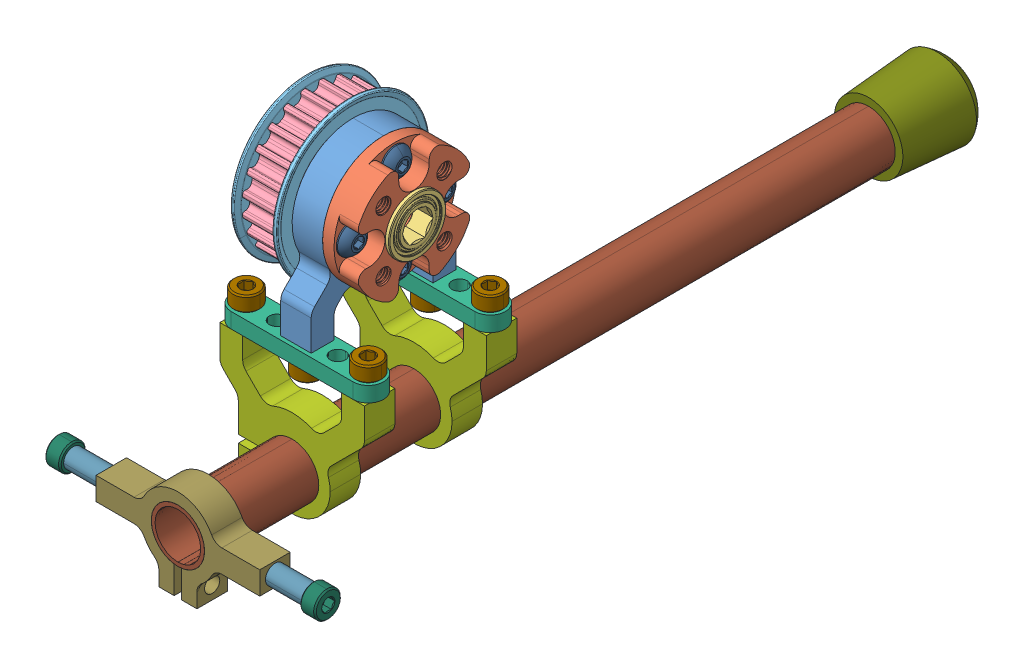
SolidWorks assembly Link4_Assembly, configuration Default. Lengths in mm.
Overall size (71.02 98.08 204.48).
44 component instances, 17 part files, 56 mates.
Components (placement in the parent):
- 1200-0032-0001-1: 1200-0032-0001 [Default] at (-4 0 0) x (0 0 -1) z (0 -1 0) size (38 8.01 40)
- 1505-0032-0080-1: 1505-0032-0080 [Default] at (4 0 0) x (0 -0.707107 -0.707107) z (0 -0.707107 0.707107) size (31.97 8.01 31.97)
- 1611-0514-4008-1: 1611-0514-4008 [Default] at (8 0 0) x (0 -0.88626 -0.463188) z (0 -0.463188 0.88626) size (15 5 15)
- 3411-0014-0024 Assembly-1: 3411-0014-0024 Assembly [Default] at (-5.9537 9.4234 37.3045) x (-1 0 0) z (0 -0.707107 -0.707107) size (12.11 52.82 52.82)
  - 3411-0014-0024 Assembly.STEP-1: 3411-0014-0024 Assembly.STEP [Default] at origin size (12.11 52.82 52.82)
    - 3411-0014-0024 Body.STEP-1: 3411-0014-0024 Body.STEP [Default] at (-9.2805 19.7149 33.0416) size (12.02 36.82 36.82)
    - 3411-0014-0024 Ring.STEP-1: 3411-0014-0024 Ring.STEP [Default] at (-0.5737 19.7149 33.0416) x (0 1 0) z (0 0 1) size (40.44 1.43 40.44)
    - 3411-0014-0024 Ring.STEP-2: 3411-0014-0024 Ring.STEP [Default] at (8.6763 19.7149 33.0416) x (0 0.381849 -0.924225) z (0 -0.924225 -0.381849) size (40.44 1.43 40.44)
- 1611-0514-4008-2: 1611-0514-4008 [Default] at (-12.01 0 0) x (0 -0.997513 -0.070476) z (0 0.070476 -0.997513) size (15 5 15)
- 1102-0005-0040-2: 1102-0005-0040 [Default] at (0 -28 -16) size (40 4 8)
- 1400-0032-0014 assembly-1: 1400-0032-0014 assembly [Default] at (-6.7355 -44.9859 -19.629) x (-1 0 0) z (0 0 1) size (38 34 8)
  - 1400-0032-0014 assembly.STEP-1: 1400-0032-0014 assembly.STEP [Default] at origin size (38 34 8)
    - 1400-0032-0014.STEP-1: 1400-0032-0014.STEP [Default] at (-6.7355 7.0141 -0.371) size (38 34 8)
    - 2800-0004-0012_90128A207.STEP-1: 2800-0004-0012_90128A207.STEP [Default] at (3.8927 0.0141 3.629) x (1 0 0) z (0 -1 0) size (7 7 16.01)
- 2800-0004-0010-1: 2800-0004-0010 [Default] at (16 -34 -16) x (1 0 0) z (0 -1 0) size (7 7 14.01)
- 2800-0004-0010-3: 2800-0004-0010 [Default] at (-16 -34 -16) x (0.99955 0 0.030006) z (0 -1 0) size (7 7 14.01)
- 2800-0004-0010-4: 2800-0004-0010 [Default] at (0 -18 -16) x (-0.87492 0 -0.484268) z (0 1 0) size (7 7 14.01)
- 2800-0004-0010-5: 2800-0004-0010 [Default] at (-16 -34 16) x (0.99955 0 -0.030006) z (0 -1 0) size (7 7 14.01)
- 1102-0005-0040-3: 1102-0005-0040 [Default] at (0 -28 16) size (40 4 8)
- 2800-0004-0010-6: 2800-0004-0010 [Default] at (0 -18 16) x (-0.87492 0 0.484268) z (0 1 0) size (7 7 14.01)
- 2800-0004-0010-7: 2800-0004-0010 [Default] at (16 -34 16) x (1 0 0) z (0 -1 0) size (7 7 14.01)
- 1400-0032-0014 assembly-4: 1400-0032-0014 assembly [Default] at (-6.7355 -44.9859 12.371) x (-1 0 0) z (0 0 1) size (38 34 8)
  - 1400-0032-0014 assembly.STEP-1: 1400-0032-0014 assembly.STEP [Default] at origin size (38 34 8)
    - 1400-0032-0014.STEP-1: 1400-0032-0014.STEP [Default] at (-6.7355 7.0141 -0.371) size (38 34 8)
    - 2800-0004-0012_90128A207.STEP-1: 2800-0004-0012_90128A207.STEP [Default] at (3.8927 0.0141 3.629) x (1 0 0) z (0 -1 0) size (7 7 16.01)
- 2800-0004-0010-16: 2800-0004-0010 [Default] at (-1.91 11.3137 0) x (0 -0.40941 0.912351) z (1 0 0) size (7 7 14.01)
- 2800-0004-0010-17: 2800-0004-0010 [Default] at (-1.91 0 -11.3137) x (0 -0.40941 0.912351) z (1 0 0) size (7 7 14.01)
- 2800-0004-0010-18: 2800-0004-0010 [Default] at (-1.91 -11.3137 0) x (0 -0.40941 0.912351) z (1 0 0) size (7 7 14.01)
- 2800-0004-0010-19: 2800-0004-0010 [Default] at (-1.91 0 11.3137) x (0 -0.40941 0.912351) z (1 0 0) size (7 7 14.01)
- 2802-0004-0008-1: 2802-0004-0008 [Default] at (9.2 -11.6137 0) x (0 0 -1) z (1 0 0) size (7.6 7.6 10.21)
- 2802-0004-0008-2: 2802-0004-0008 [Default] at (9.2 11.6137 0) x (0 0 -1) z (1 0 0) size (7.6 7.6 10.21)
- 2802-0004-0008-3: 2802-0004-0008 [Default] at (9.2 0 -11.6137) x (0 0 -1) z (1 0 0) size (7.6 7.6 10.21)
- 2802-0004-0008-4: 2802-0004-0008 [Default] at (9.2 0 11.6137) x (0 0 -1) z (1 0 0) size (7.6 7.6 10.21)
- 4100-1214-0200-1: 4100-1214-0200 [Default] at (0 -52 50) x (1 0 0) z (0 1 0) size (14 200 14)
- 1402-0043-0014-1: 1402-0043-0014 [Default] at (-3.9775 -62.2331 37.3554) x (0 -1 0) z (0 0 1) size (24.13 43.01 18.01)
  - 1402-0043-0014.step-1: 1402-0043-0014.step [Default] at origin size (24.13 43.01 18.01)
    - 1402-0043-0014 without hardware.step-1: 1402-0043-0014 without hardware.step [Default] at (-10.2331 3.9775 4.6446) x (0 -1 0) z (1 0 0) size (43.01 8 24.13)
    - 2800-0004-0010.step-1: 2800-0004-0010.step [Default] at (0.3951 -1.0225 8.6446) size (7 7 14.01)
- 1502-0005-0100-1: 1502-0005-0100 [Default] at (-21.5 -52 46) x (0 1 0) z (0 0 1) size (5 10 5)
- 2800-0004-0018-1: 2800-0004-0018 [Default] at (-13.5 -52 46) x (0 -0.999802 -0.019876) z (1 0 0) size (7 7 22.01)
- 2800-0004-0018-2: 2800-0004-0018 [Default] at (13.5 -52 46) x (0 -0.999802 -0.019876) z (-1 0 0) size (7 7 22.01)
- 14mm Chair leg tip cap-1: 14mm Chair leg tip cap [Default] at (0 -52 -150) x (-0.792237 0.610214 0) z (0.610214 0.792237 0) size (20.65 23.07 20.65)
- Linear_Disp_Sensor_404R1KL1.0-1: Linear_Disp_Sensor_404R1KL1.0 [Default] at (-11.95 -52 -127.2937) x (0 0 -1) z (1 0 0) size (47.49 12.7 8.51) (hidden)
- 1502-0005-0100-3: 1502-0005-0100 [Default] at (21.5 -52 46) x (0 1 0) z (0 0 -1) size (5 10 5)
Mates (geometry in assembly coordinates):
- Coincident1: coincident anti-aligned: plane of 1200-0032-0001-1 through (-4 0 0) normal (0 -1 0)
- Symmetric1: symmetric aligned: plane of 1200-0032-0001-1 through (4 0 0) normal (1 0 0); plane of 1200-0032-0001-1 through (-4 0 0) normal (-1 0 0)
- Symmetric2: symmetric aligned: plane of 1200-0032-0001-1 through (-22.0392 0 -19) normal (0 0 -1); plane of 1200-0032-0001-1 through (-22.0392 0 19) normal (0 0 1)
- Concentric2: concentric anti-aligned: cylinder of 1200-0032-0001-1 through (4 0 0) axis (-1 0 0) radius 7; cylinder of 1505-0032-0080-1 through (4 0 0) axis (1 0 0) radius 7
- Coincident2: coincident anti-aligned: circle of 1200-0032-0001-1; cylinder of 1505-0032-0080-1 through (4 0 11.3137) axis (1 0 0) radius 2
- Coincident3: coincident anti-aligned: plane of 1200-0032-0001-1 through (4 0 0) normal (1 0 0); plane of 1505-0032-0080-1 through (4 0 0) normal (-1 0 0)
- Concentric3: concentric aligned: cylinder of 1200-0032-0001-1 through (4 0 0) axis (-1 0 0) radius 7; cylinder of 3411-0014-0024 Assembly-1/3411-0014-0024 Assembly.STEP-1/3411-0014-0024 Body.STEP-1 through (-11.91 0 0) axis (-1 0 0) radius 7
- Concentric4: concentric anti-aligned: circle of 1200-0032-0001-1; cylinder of 3411-0014-0024 Assembly-1/3411-0014-0024 Assembly.STEP-1/3411-0014-0024 Body.STEP-1 through (-4 11.3137 0) axis (-1 0 0) radius 2
- Coincident5: coincident anti-aligned: plane of 1200-0032-0001-1 through (-4 0 0) normal (-1 0 0); plane of 3411-0014-0024 Assembly-1/3411-0014-0024 Assembly.STEP-1/3411-0014-0024 Body.STEP-1 through (-4 0 0) normal (1 0 0)
- Concentric5: concentric anti-aligned: cylinder of 1505-0032-0080-1 through (4 0 0) axis (1 0 0) radius 7; cylinder of 1611-0514-4008-1 through (12 0 0) axis (-1 0 0) radius 7
- Coincident6: coincident anti-aligned: plane of 1505-0032-0080-1 through (12 0 0) normal (1 0 0); plane of 1611-0514-4008-1 through (12 0 0) normal (-1 0 0)
- Concentric6: concentric anti-aligned: cylinder of 3411-0014-0024 Assembly-1/3411-0014-0024 Assembly.STEP-1/3411-0014-0024 Body.STEP-1 through (-11.91 0 0) axis (-1 0 0) radius 7; cylinder of 1611-0514-4008-2 through (-16.01 0 0) axis (1 0 0) radius 7
- Coincident8: coincident anti-aligned: plane of 3411-0014-0024 Assembly-1/3411-0014-0024 Assembly.STEP-1/3411-0014-0024 Body.STEP-1 through (-16.01 0 0) normal (-1 0 0); plane of 1611-0514-4008-2 through (-16.01 0 0) normal (1 0 0)
- Coincident12: coincident anti-aligned: plane of 1200-0032-0001-1 through (-22.0392 -24 0) normal (0 -1 0); plane of 1102-0005-0040-2 through (-16 -24 -16) normal (0 1 0)
- Coincident13: coincident aligned: circle of 1200-0032-0001-1; cylinder of 1102-0005-0040-2 through (0 -24 -16) axis (0 1 0) radius 2
- Parallel2: parallel aligned: plane of 1200-0032-0001-1 through (-22.0392 0 -19) normal (0 0 -1); plane of 1102-0005-0040-2 through (-16 -24 -20) normal (0 0 -1)
- Coincident14: coincident anti-aligned: plane of 1102-0005-0040-2 through (-16 -28 -16) normal (0 -1 0); plane of 1400-0032-0014 assembly-1/1400-0032-0014 assembly.STEP-1/1400-0032-0014.STEP-1 through (13 -28 -12) normal (0 1 0)
- Coincident15: coincident anti-aligned: cylinder of 1102-0005-0040-2 through (16 -24 -16) axis (0 1 0) radius 2; circle of 1400-0032-0014 assembly-1/1400-0032-0014 assembly.STEP-1/1400-0032-0014.STEP-1
- Coincident16: coincident aligned: plane of 1102-0005-0040-2 through (-16 -24 -20) normal (0 0 -1); plane of 1400-0032-0014 assembly-1/1400-0032-0014 assembly.STEP-1/1400-0032-0014.STEP-1 through (0 -52 -20) normal (0 0 -1)
- Coincident22: coincident anti-aligned: plane of 1102-0005-0040-2 through (-16 -24 -16) normal (0 1 0); plane of 2800-0004-0010-1 through (16 -24 -16) normal (0 -1 0)
- Concentric10: concentric anti-aligned: cylinder of 1102-0005-0040-2 through (16 -24 -16) axis (0 1 0) radius 2; cylinder of 2800-0004-0010-1 through (16 -20 -16) axis (0 -1 0) radius 3.5
- Concentric11: concentric anti-aligned: cylinder of 1102-0005-0040-2 through (-16 -24 -16) axis (0 1 0) radius 2; cylinder of 2800-0004-0010-3 through (-16 -20 -16) axis (0 -1 0) radius 3.5
- Coincident23: coincident anti-aligned: plane of 1102-0005-0040-2 through (-16 -24 -16) normal (0 1 0); plane of 2800-0004-0010-3 through (-16 -24 -16) normal (0 -1 0)
- Concentric12: concentric aligned: cylinder of 1102-0005-0040-2 through (0 -24 -16) axis (0 1 0) radius 2; cylinder of 2800-0004-0010-4 through (0 -32 -16) axis (0 1 0) radius 3.5
- Coincident24: coincident anti-aligned: plane of 1102-0005-0040-2 through (-16 -28 -16) normal (0 -1 0); plane of 2800-0004-0010-4 through (0 -28 -16) normal (0 1 0)
- Coincident29: coincident aligned: plane of 2800-0004-0010-16 through (-11.91 11.3137 0) normal (1 0 0); plane of 2800-0004-0010-17 through (-11.91 0 -11.3137) normal (1 0 0)
- Coincident30: coincident aligned: plane of 2800-0004-0010-17 through (-11.91 0 -11.3137) normal (1 0 0); plane of 2800-0004-0010-18 through (-11.91 -11.3137 0) normal (1 0 0)
- Coincident31: coincident aligned: plane of 2800-0004-0010-17 through (-11.91 0 -11.3137) normal (1 0 0); plane of 2800-0004-0010-19 through (-11.91 0 11.3137) normal (1 0 0)
- Coincident32: coincident anti-aligned: plane of 3411-0014-0024 Assembly-1/3411-0014-0024 Assembly.STEP-1/3411-0014-0024 Body.STEP-1 through (-11.91 0 0) normal (-1 0 0); plane of 2800-0004-0010-17 through (-11.91 0 -11.3137) normal (1 0 0)
- Concentric17: concentric anti-aligned: cylinder of 3411-0014-0024 Assembly-1/3411-0014-0024 Assembly.STEP-1/3411-0014-0024 Body.STEP-1 through (-11.91 0 -11.3137) axis (-1 0 0) radius 3.6; cylinder of 2800-0004-0010-17 through (-15.91 0 -11.3137) axis (1 0 0) radius 3.5
- Concentric18: concentric anti-aligned: cylinder of 3411-0014-0024 Assembly-1/3411-0014-0024 Assembly.STEP-1/3411-0014-0024 Body.STEP-1 through (-11.91 11.3137 0) axis (-1 0 0) radius 3.6; cylinder of 2800-0004-0010-16 through (-15.91 11.3137 0) axis (1 0 0) radius 3.5
- Concentric19: concentric anti-aligned: cylinder of 3411-0014-0024 Assembly-1/3411-0014-0024 Assembly.STEP-1/3411-0014-0024 Body.STEP-1 through (-11.91 0 11.3137) axis (-1 0 0) radius 3.6; cylinder of 2800-0004-0010-19 through (-15.91 0 11.3137) axis (1 0 0) radius 3.5
- Concentric20: concentric anti-aligned: cylinder of 3411-0014-0024 Assembly-1/3411-0014-0024 Assembly.STEP-1/3411-0014-0024 Body.STEP-1 through (-11.91 -11.3137 0) axis (-1 0 0) radius 3.6; cylinder of 2800-0004-0010-18 through (-15.91 -11.3137 0) axis (1 0 0) radius 3.5
- Coincident33: coincident aligned: plane of 2802-0004-0008-1 through (7 -15.4137 0) normal (-1 0 0); plane of 2802-0004-0008-3 through (7 -3.8 -11.6137) normal (-1 0 0)
- Coincident34: coincident aligned: plane of 2802-0004-0008-3 through (7 -3.8 -11.6137) normal (-1 0 0); plane of 2802-0004-0008-4 through (7 -3.8 11.6137) normal (-1 0 0)
- Coincident35: coincident aligned: plane of 2802-0004-0008-2 through (7 7.8137 0) normal (-1 0 0); plane of 2802-0004-0008-4 through (7 -3.8 11.6137) normal (-1 0 0)
- Coincident36: coincident anti-aligned: plane of 1505-0032-0080-1 through (7 15.4764 0) normal (1 0 0); plane of 2802-0004-0008-2 through (7 7.8137 0) normal (-1 0 0)
- Concentric21: concentric aligned: cylinder of 1505-0032-0080-1 through (7 11.6137 0) axis (1 0 0) radius 4; circle of 2802-0004-0008-2
- Concentric22: concentric aligned: cylinder of 1505-0032-0080-1 through (7 0 -11.6137) axis (1 0 0) radius 4; circle of 2802-0004-0008-3
- Concentric24: concentric aligned: cylinder of 1505-0032-0080-1 through (7 -11.6137 0) axis (1 0 0) radius 4; circle of 2802-0004-0008-1
- Concentric25: concentric aligned: cylinder of 1505-0032-0080-1 through (7 0 11.6137) axis (1 0 0) radius 4; circle of 2802-0004-0008-4
- Concentric26: concentric anti-aligned: cylinder of 1400-0032-0014 assembly-4/1400-0032-0014 assembly.STEP-1/1400-0032-0014.STEP-1 through (0 -52 20) axis (0 0 -1) radius 7; cylinder of 4100-1214-0200-1 through (0 -52 -150) axis (0 0 1) radius 7
- Distance1: distance = 30 mm aligned: plane of 1400-0032-0014 assembly-4/1400-0032-0014 assembly.STEP-1/1400-0032-0014.STEP-1 through (0 -52 20) normal (0 0 1); plane of 4100-1214-0200-1 through (0 -52 50) normal (0 0 1)
- Coincident38: coincident aligned: plane of 4100-1214-0200-1 through (0 -52 50) normal (1 0 0)
- Concentric27: concentric aligned: cylinder of 4100-1214-0200-1 through (0 -52 -150) axis (0 0 1) radius 7; cylinder of 1402-0043-0014-1/1402-0043-0014.step-1/1402-0043-0014 without hardware.step-1 through (0 -52 50) axis (0 0 1) radius 7
- Coincident39: coincident aligned: plane of 4100-1214-0200-1 through (0 -52 50) normal (0 0 1); plane of 1402-0043-0014-1/1402-0043-0014.step-1/1402-0043-0014 without hardware.step-1 through (0 -52 50) normal (0 0 1)
- Parallel3: parallel aligned: plane of 1102-0005-0040-3 through (-16 -28 16) normal (0 -1 0); plane of 1402-0043-0014-1/1402-0043-0014.step-1/1402-0043-0014 without hardware.step-1 through (0 -66.1282 35.2252) normal (0 -1 0)
- Coincident40: coincident anti-aligned: plane of 1402-0043-0014-1/1402-0043-0014.step-1/1402-0043-0014 without hardware.step-1 through (-21.5 -52 50) normal (-1 0 0); plane of 1502-0005-0100-1 through (-21.5 -52 46) normal (1 0 0)
- Concentric28: concentric aligned: circle of 1402-0043-0014-1/1402-0043-0014.step-1/1402-0043-0014 without hardware.step-1; cylinder of 1502-0005-0100-1 through (-31.5 -52 46) axis (1 0 0) radius 2.5
- Concentric29: concentric aligned: cylinder of 1502-0005-0100-1 through (-31.5 -52 46) axis (1 0 0) radius 2.5; cylinder of 2800-0004-0018-1 through (-35.5 -52 46) axis (1 0 0) radius 3.5
- Coincident41: coincident anti-aligned: plane of 1502-0005-0100-1 through (-31.5 -52 46) normal (-1 0 0); plane of 2800-0004-0018-1 through (-31.5 -52 46) normal (1 0 0)
- Concentric30: concentric aligned: cylinder of 4100-1214-0200-1 through (0 -52 -150) axis (0 0 1) radius 7; cylinder of 14mm Chair leg tip cap-1 through (0 -52 -150) axis (0 0 1) radius 7
- Coincident42: coincident anti-aligned: plane of 4100-1214-0200-1 through (0 -52 -150) normal (0 0 -1); circle of 14mm Chair leg tip cap-1
- Parallel4: parallel aligned: plane of Linear_Disp_Sensor_404R1KL1.0-1 through (-7 -52 -127.2937) normal (1 0 0)
- Symmetric3: symmetric aligned: plane of 4100-1214-0200-1 through (0 -52 50) normal (0 1 0); plane of Linear_Disp_Sensor_404R1KL1.0-1 through (-15.51 -58.35 -140.7537) normal (0 -1 0); plane of Linear_Disp_Sensor_404R1KL1.0-1 through (-15.51 -45.65 -140.7537) normal (0 1 0)
- Tangent1: tangent anti-aligned: cylinder of 4100-1214-0200-1 through (0 -52 -150) axis (0 0 1) radius 7; plane of Linear_Disp_Sensor_404R1KL1.0-1 through (-7 -52 -127.2937) normal (1 0 0)
